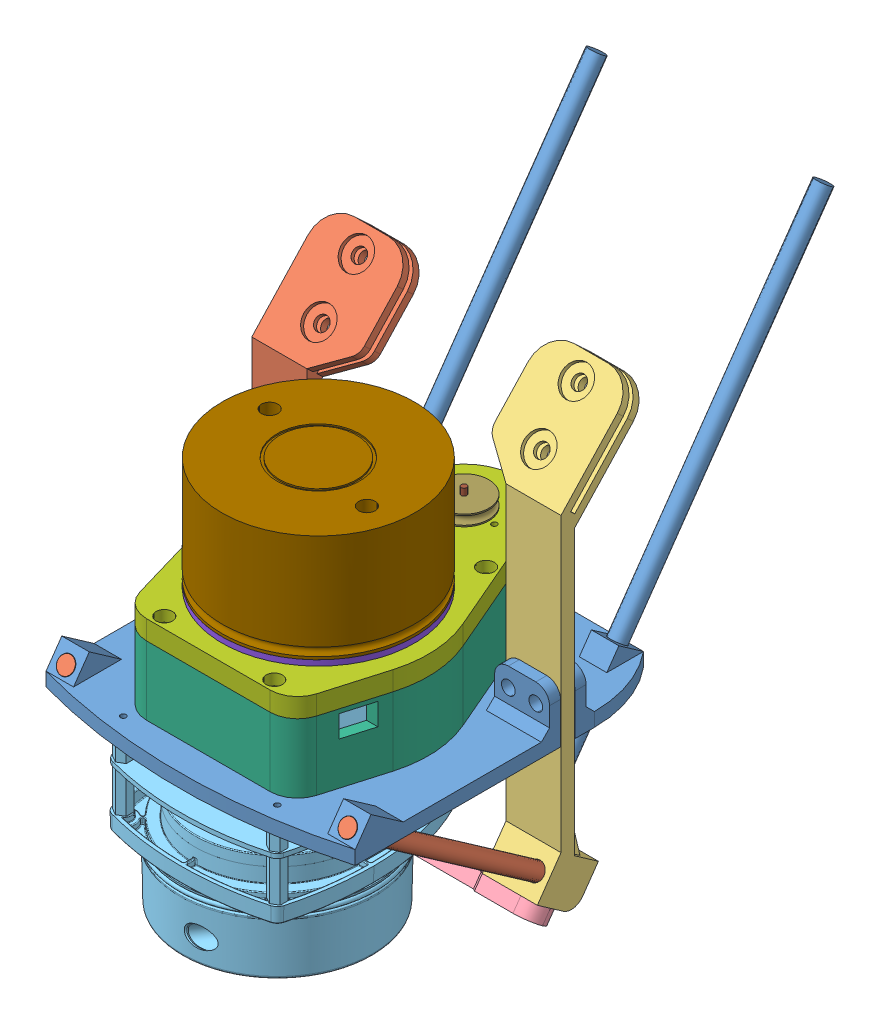
SolidWorks assembly Lidar_support, configuration Default. Lengths in mm.
Overall size (112.45 173.87 208.81).
25 component instances, 20 part files, 21 mates.
Components (placement in the parent):
- Tray_indep-1: Tray_indep [Default] at (34.0393 -36.4517 -24.9167) size (112.45 20 122.49)
- Pillar_left-1: Pillar_left [Default] at (-56.2273 97.088 -102.104) size (32.45 155.29 41.73)
- Pillar_right-1: Pillar_right [Default] at (-3.7727 97.088 -102.104) size (32.45 155.29 41.73)
- Pillar_base-1: Pillar_base [Default] at origin size (112.45 10.75 12.38)
- RPLidar-1: RPLidar [Default] at (132.9176 714.6923 -118.4212) x (0 0 -1) z (-1 0 0) size (116.38 53.5 95.72)
- LidarBeta-1: LidarBeta [Default] at (0 -12.073 -42.7903) x (-1 0 0) z (0 0 -1) size (80 70.71 112)
  - Cover_base-1: Cover_base [Default] at origin size (80 25 112)
  - Cover_top-1: Cover_top [Default] at origin size (80 8 112)
  - Head_base-1: Head_base [Default] at (0 37.0834 0) x (-0.258111 0 0.966115) z (-0.966115 0 -0.258111) size (70 58 70)
  - Head_top-1: Head_top [Default] at (0 15.2712 0) x (0.966115 0 0.258111) z (-0.258111 0 0.966115) size (70 39 70)
  - 6810-1: 6810 [Default] at (0 40.5782 0) x (0 1 0) z (0.911895 0 -0.410424) size (7.01 65 65)
  - RF-530-1: RF-530 [Default] at (0 22.073 53) size (33 31.5 33)
  - Pulley-1: Pulley [Default] at (0 -2.4896 0) size (18 4 18)
  - Slipring_v1.1-1: Slipring_v1.1 [Default] at (0 46.0834 0) x (-0.672958 0 -0.739681) z (-0.739681 0 0.672958) size (22 17 22)
  - Lidar_PCB-1: Lidar_PCB [Default] at (0 17.073 0) x (0 0 1) z (-1 0 0) size (64 7.6 60)
  - Lidar_Lite_V2-1: Lidar_Lite_V2 [Default] at (-19.3223 65.0834 -5.1622) x (0.258111 0 -0.966115) z (0.966115 0 0.258111) size (48 35.4 39.5)
    - Garmin_Lidar_Lite_3.step-1: Garmin_Lidar_Lite_3.step [Default] at origin size (48 35.4 39.5)
      - Garmin_Lidar_Lite_31.step-1: Garmin_Lidar_Lite_31.step [Default] at origin size (48 35.4 5)
      - Garmin_Lidar_Lite_32.step-1: Garmin_Lidar_Lite_32.step [Default] at origin size (48 20 37)
      - Garmin_Lidar_Lite_33.step-1: Garmin_Lidar_Lite_33.step [Default] at origin size (12.5 4.5 2)
      - Garmin_Lidar_Lite_34.step-1: Garmin_Lidar_Lite_34.step [Default] at origin size (10.35 3.3 4.35)
- Rod_large-1: Rod_large [Default] at (-41.2273 -53.6529 -70.5222) x (0.433901 -0.51677 -0.738023) z (0.90096 0.248876 0.355431) size (6 200 6)
- Rod_small-1: Rod_small [Default] at (-51.2273 -54.0225 -84.1259) x (-0.631991 -0.634823 0.444508) z (-0.774976 0.517697 -0.362495) size (6 100 6)
- Rod_large-2: Rod_large [Default] at (41.2273 -53.6529 -70.5222) x (1 0 0) z (0 0.573576 0.819152) size (6 200 6)
- Rod_small-2: Rod_small [Default] at (51.2273 -54.0225 -84.1259) x (-0.88217 0.385765 -0.270115) z (0.470932 0.722631 -0.505992) size (6 100 6)
Mates (geometry in assembly coordinates):
- Coincident1: coincident anti-aligned: plane of Tray_indep-1 through (0 -36.4517 -24.9167) normal (-1 0 0)
- Coincident2: coincident aligned: plane of Tray_indep-1 through (34.0393 0 -24.9167) normal (0 1 0)
- Coincident4: coincident aligned: plane of Pillar_left-1 through (-36.2273 67.8339 -74.824) normal (0 0 1); plane of Pillar_right-1 through (36.2273 67.8339 -74.824) normal (0 0 1)
- Coincident5: coincident aligned: plane of Pillar_left-1 through (-36.2273 97.088 -102.104) normal (0 0.681998 0.731354); plane of Pillar_right-1 through (36.2273 97.088 -102.104) normal (0 0.681998 0.731354)
- Coincident9: coincident aligned: plane of Tray_indep-1 through (-56.2273 -5 -24.9167) normal (-1 0 0); plane of Pillar_left-1 through (-56.2273 97.088 -102.104) normal (-1 0 0)
- Coincident10: coincident aligned: plane of Tray_indep-1 through (56.2273 -5 -24.9167) normal (1 0 0); plane of Pillar_right-1 through (56.2273 97.088 -102.104) normal (1 0 0)
- Concentric3: concentric anti-aligned: cylinder of Tray_indep-1 through (-51.2273 -52.318 -81.6916) axis (0 0.573576 0.819152) radius 3.1; cylinder of Pillar_left-1 through (-51.2273 4.1042 -1.1124) axis (0 -0.573576 -0.819152) radius 3.1
- Concentric4: concentric anti-aligned: cylinder of Tray_indep-1 through (51.2273 -52.318 -81.6916) axis (0 0.573576 0.819152) radius 3.1; cylinder of Pillar_right-1 through (51.2273 4.1042 -1.1124) axis (0 -0.573576 -0.819152) radius 3.1
- Distance4: distance = 0.15 mm anti-aligned: plane of Pillar_right-1 through (36.2273 67.8339 -74.824) normal (0 0 1); plane of Tray_indep-1 through (34.0393 -5 -74.674) normal (0 0 -1)
- Concentric5: concentric aligned: cylinder of Pillar_left-1 through (-51.2273 4.1042 -1.1124) axis (0 -0.573576 -0.819152) radius 3.1; cylinder of Rod_small-1 through (-51.2273 3.3352 -2.2107) axis (0 -0.573576 -0.819152) radius 3
- Coincident12: coincident aligned: plane of Pillar_left-1 through (-46.2273 55.8212 -161.0392) normal (0 -0.573576 -0.819152); plane of Rod_small-1 through (-51.2273 -54.0225 -84.1259) normal (0 -0.573576 -0.819152)
- Concentric6: concentric aligned: cylinder of Pillar_left-1 through (-41.2273 65.0834 -153.6622) axis (0 -0.819152 0.573576) radius 3.1; cylinder of Rod_large-1 through (-41.2273 110.1775 -185.2375) axis (0 -0.819152 0.573576) radius 3
- Coincident13: coincident aligned: plane of Pillar_left-1 through (-46.2273 -18.8992 -20.8888) normal (0 -0.819152 0.573576); plane of Rod_large-1 through (-41.2273 -53.6529 -70.5222) normal (0 -0.819152 0.573576)
- Concentric7: concentric anti-aligned: cylinder of Tray_indep-1 through (51.2273 -52.318 -81.6916) axis (0 0.573576 0.819152) radius 3.1; cylinder of Rod_small-2 through (51.2273 3.3352 -2.2107) axis (0 -0.573576 -0.819152) radius 3
- Coincident14: coincident aligned: plane of Rod_small-1 through (-51.2273 -54.0225 -84.1259) normal (0 -0.573576 -0.819152); plane of Rod_small-2 through (51.2273 -54.0225 -84.1259) normal (0 -0.573576 -0.819152)
- Concentric8: concentric aligned: cylinder of Pillar_right-1 through (41.2273 65.0834 -153.6622) axis (0 -0.819152 0.573576) radius 3.1; cylinder of Rod_large-2 through (41.2273 110.1775 -185.2375) axis (0 -0.819152 0.573576) radius 3
- Coincident15: coincident aligned: plane of Rod_large-1 through (-41.2273 -53.6529 -70.5222) normal (0 -0.819152 0.573576); plane of Rod_large-2 through (41.2273 -53.6529 -70.5222) normal (0 -0.819152 0.573576)
- Tangent1: tangent anti-aligned: plane of Tray_indep-1 through (34.0393 -5 -24.9167) normal (0 -1 0); face of RPLidar-1
- Coincident16: coincident anti-aligned: plane of RPLidar-1 through (0 714.6923 -118.4212) normal (-1 0 0)
- Coincident17: coincident anti-aligned: plane of Tray_indep-1 through (34.0393 0 -24.9167) normal (0 1 0); plane of ? through (22.5 0 -12.7903) normal (0 -1 0)
- Coincident18: coincident anti-aligned: plane of LidarBeta-1 through (0 -12.073 -42.7903) normal (-1 0 0)
